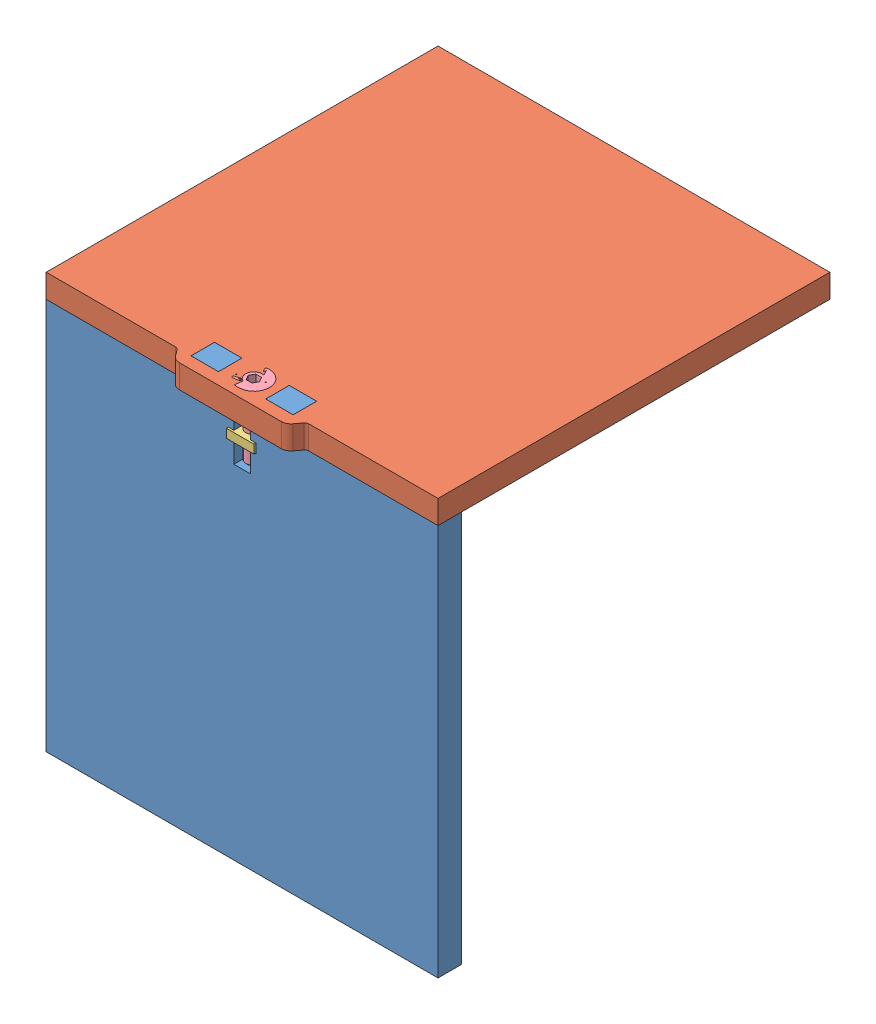
SolidWorks assembly auto_mount_m4_din, configuration По умолчанию. Lengths in mm.
Overall size (100 106 107.79).
4 component instances, 4 part files, 11 mates.
Components (placement in the parent):
- plywood_test_m4_16din-1: plywood_test_m4_16din [По умолчанию] at (51.7183 54.318 64.1682) size (100 106 6)
- plywood_test2_m4_16din-2: plywood_test2_m4_16din [По умолчанию] at (51.7183 104.318 20.1682) x (-1 0 0) z (0 1 0) size (100 103 6)
- din 562 m4din-1: din 562 m4din [По умолчанию] at (51.7183 99.318 67.1682) x (1 0 0) z (0 -1 0) size (7 7 2.2)
- DIN 7991-1: DIN 7991 [ISO 7991 M04 x  16] at (51.7183 110.318 67.1682) x (0 -1 0) z (0 0 1) size (18.3 40 22.08)
Mates (geometry in assembly coordinates):
- Совпадение1: coincident aligned: plane of plywood_test-1 through (51.7183 54.318 70.1682) normal (0 0 1); plane of plywood_test2-2 through (101.7183 110.318 70.1682) normal (0 0 1)
- Совпадение2: coincident anti-aligned: plane of plywood_test-1 through (1.7183 104.318 70.1682) normal (0 1 0); plane of plywood_test2_m4_16din-2 through (51.7183 104.318 20.1682) normal (0 -1 0)
- Совпадение3: coincident aligned: plane of plywood_test-1 through (101.7183 4.318 70.1682) normal (1 0 0); plane of plywood_test2_m4_16din-2 through (101.7183 110.318 -29.8318) normal (1 0 0)
- Совпадение8: coincident anti-aligned: plane of plywood_test-1 through (49.6183 99.318 64.1682) normal (0 -1 0); plane of din 562 m4-1 through (51.7183 99.318 67.1682) normal (0 1 0)
- Совпадение11: coincident anti-aligned: plane of plywood_test2_m4_16din-2 through (101.7183 110.318 70.1682) normal (0 0 1); plane of DIN 7991-1 through (51.7183 110.318 70.1682) normal (0 0 -1)
- Совпадение16: coincident anti-aligned: plane of plywood_test2_m4_16din-2 through (101.7183 110.318 70.1682) normal (0 0 1); plane of DIN 7991-1 through (51.7183 110.318 70.1682) normal (0 0 -1)
- Совпадение18: coincident anti-aligned: plane of plywood_test2_m4_16din-2 through (101.7183 110.318 70.1682) normal (0 0 1); plane of DIN 7991-1 through (51.7183 110.318 70.1682) normal (0 0 -1)
- Совпадение20: coincident anti-aligned: plane of plywood_test2_m4_16din-2 through (101.7183 110.318 70.1682) normal (0 0 1); plane of DIN 7991-1 through (51.7183 110.318 70.1682) normal (0 0 -1)
- Совпадение21: coincident aligned: plane of plywood_test2_m4_16din-2 through (51.7183 110.318 20.1682) normal (0 1 0); plane of DIN 7991-1 through (51.7183 110.318 67.1682) normal (0 1 0)
- Совпадение29: coincident: point of din 562 m4din-1; line of DIN 7991-1 through (51.7183 92.018 67.1682) axis (0 1 0)
- Совпадение32: coincident: line of DIN 7991-1 through (51.7183 92.018 67.1682) axis (0 1 0)
